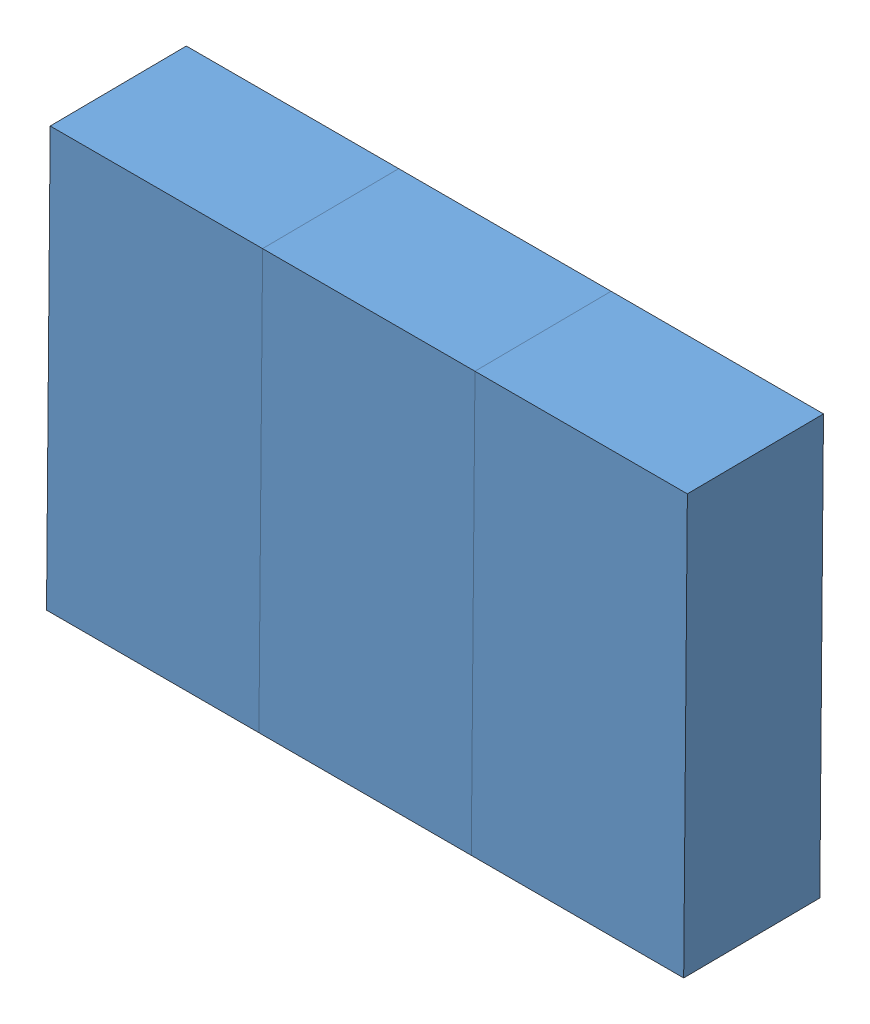
SolidWorks assembly Heat Treat Asm Side, configuration Default. Lengths in mm.
Overall size (347.64 233.01 78.01).
3 component instances, 1 part files, 6 mates.
Components (placement in the parent):
- Brick-Sharp-1: Brick-Sharp [Default] at (91.3299 124.3408 170.7235) x (-0.008727 -0.999962 0) z (-0.999924 0.008726 0.008727) size (230 75 115)
- Brick-Sharp-2: Brick-Sharp [Default] at (206.3211 123.3373 169.7199) x (0.008727 0.999962 0) z (-0.999924 0.008726 0.008727) size (230 75 115)
- Brick-Sharp-4: Brick-Sharp [Default] at (321.3124 122.3338 168.7164) x (-0.008727 -0.999962 0) z (0.999924 -0.008726 -0.008727) size (230 75 115)
Mates (geometry in assembly coordinates):
- Coincident2: coincident anti-aligned: plane of Brick-Sharp-1 through (150.1563 238.8318 207.7203) normal (0.999924 -0.008726 -0.008727); plane of Brick-Sharp-2 through (147.4947 8.8463 132.7231) normal (-0.999924 0.008726 0.008727)
- Coincident3: coincident: line of Brick-Sharp-1 through (148.1492 8.8406 207.7203) axis (0.008727 0.999962 0); plane of Brick-Sharp-2 through (206.6484 123.3345 207.2185) normal (0.008726 -0.000076 0.999962)
- Coincident4: coincident: plane of Brick-Sharp-1 through (148.1492 8.8406 207.7203) normal (-0.008727 -0.999962 0); line of Brick-Sharp-2 through (147.4947 8.8463 132.7231) axis (0.008726 -0.000076 0.999962)
- Coincident5: coincident anti-aligned: plane of Brick-Sharp-2 through (262.486 7.8428 131.7196) normal (0.999924 -0.008726 -0.008727); plane of Brick-Sharp-4 through (264.4931 237.834 131.7196) normal (-0.999924 0.008726 0.008727)
- Coincident6: coincident aligned: line of Brick-Sharp-2 through (264.4931 237.834 131.7196) axis (0.008726 -0.000076 0.999962); line of Brick-Sharp-4 through (264.4931 237.834 131.7196) axis (0.008726 -0.000076 0.999962)
- Coincident7: coincident anti-aligned: line of Brick-Sharp-2 through (265.1475 237.8283 206.7167) axis (-0.008727 -0.999962 0); line of Brick-Sharp-4 through (263.1404 7.8371 206.7167) axis (0.008727 0.999962 0)
